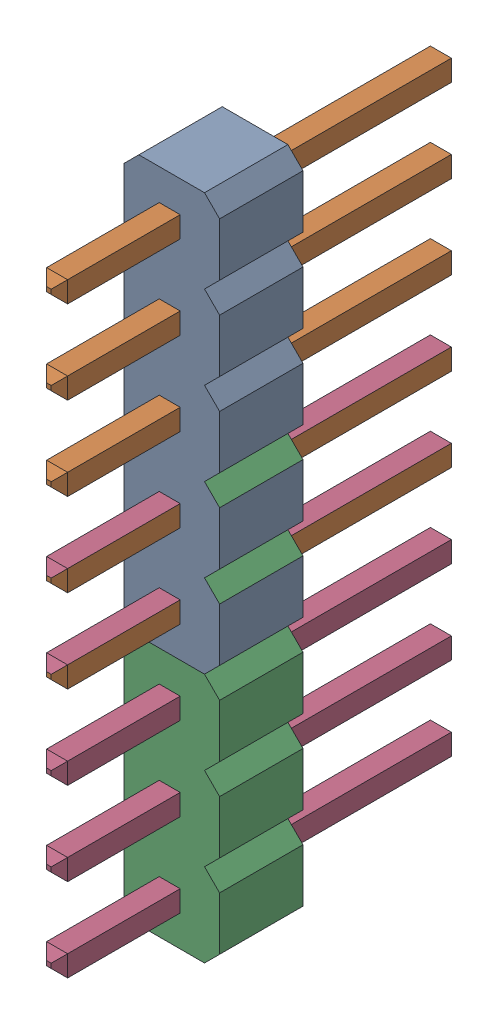
SolidWorks assembly Header_1x8.step, configuration Default. Lengths in mm.
Overall size (2.92 20.32 12.19).
8 component instances, 2 part files, 0 mates.
Components (placement in the parent):
- PCB.step-1: PCB.step [Default] at origin size (2.92 20.32 12.19)
  - Free-Models.step-1: Free-Models.step [Default] at origin size (2.92 20.32 12.19)
    - 1240637040.step-1: 1240637040.step [Default] at (97.7778 84.836 -1.6002) x (0 -1 0) z (1 0 0) size (12.7 12.19 2.92)
      - User_Library-PinHeaderX5-1_PinHeaderX5_Body_1.step-1: User_Library-PinHeaderX5-1_PinHeaderX5_Body_1.step [Default] at origin size (12.7 2.54 2.92)
      - User_Library-PinHeaderX5-1_PinHeaderX5_Pins_1.step-1: User_Library-PinHeaderX5-1_PinHeaderX5_Pins_1.step [Default] at origin size (10.8 12.19 0.64)
    - 1240637040.step-2: 1240637040.step [Default] at (97.7778 77.216 -1.6002) x (0 -1 0) z (1 0 0) size (12.7 12.19 2.92)
      - User_Library-PinHeaderX5-1_PinHeaderX5_Body_1.step-1: User_Library-PinHeaderX5-1_PinHeaderX5_Body_1.step [Default] at origin size (12.7 2.54 2.92)
      - User_Library-PinHeaderX5-1_PinHeaderX5_Pins_1.step-1: User_Library-PinHeaderX5-1_PinHeaderX5_Pins_1.step [Default] at origin size (10.8 12.19 0.64)
